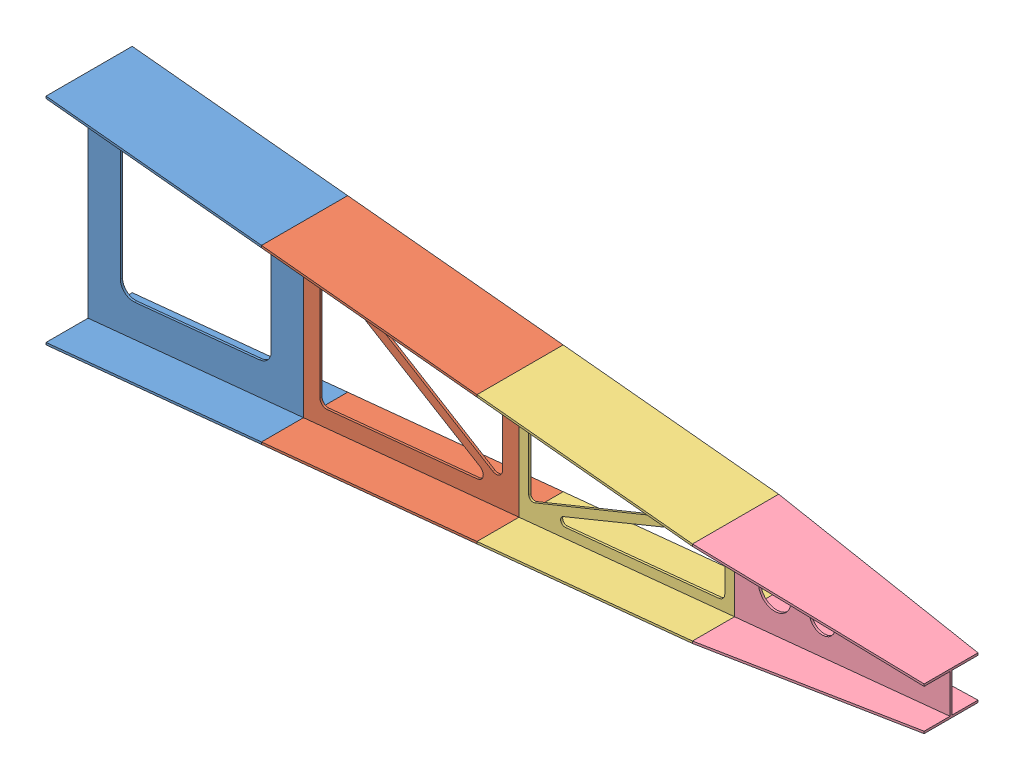
SolidWorks assembly Assembly, configuration Default. Lengths in mm.
Overall size (4000 1000 400).
4 component instances, 4 part files, 3 mates.
Components (placement in the parent):
- 1-1: 1 [Default] at (-775.9263 612.0858 1043.8579) size (1000 1000 400)
- 2-2: 2 [Default] at (224.0737 612.0858 1043.8579) size (1000 800 400)
- 3-2: 3 [Default] at (1224.0737 612.0858 1043.8579) size (1000 600 400)
- 4-2: 4 [Default] at (2224.0737 612.0858 1043.8579) size (1000 400 400)
Mates (geometry in assembly coordinates):
- Coincident8: coincident: point of 1-1; point of 2-2
- Coincident9: coincident: point of 2-2; point of 3-2
- Coincident10: coincident: point of 3-2; point of 4-2
